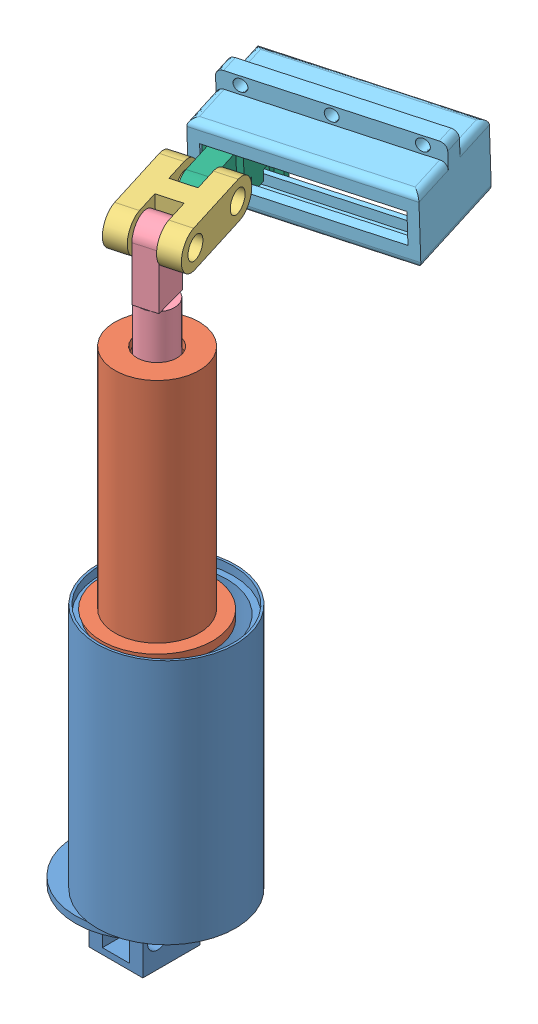
SolidWorks assembly transmission_tele_block_L, configuration Default. Lengths in mm.
Overall size (40.5 112.82 50.09).
7 component instances, 6 part files, 11 mates.
Components (placement in the parent):
- 3rd_tele_part-1: 3rd_tele_part [Default] at (-18.7629 74.2349 7.8731) size (23.75 45.5 20.5)
- 2nd_tele_part-1: 2nd_tele_part [Default] at (-16.8919 75.4849 7.8731) x (0.328664 0 0.944447) z (-0.944447 0 0.328664) size (16.5 35 16.5)
- slider_to_tele-1: slider_to_tele [Default] at (-18.5582 71.8417 -4.2402) x (-0.963773 0 0.266724) z (0.012885 0.998832 0.046558) size (9.53 15 5.5)
- telescopic link-1: telescopic link [Default] at (-15.3258 74.0088 7.4396) x (0.266724 0 0.963773) z (-0.963773 0 0.266724) size (9.2 21.75 9.2)
- transmission_assem-1: transmission_assem [Default] at (-102.7292 -14.6686 -0.1247) x (-0.391198 -0.119011 -0.912579) z (0.837007 0.36623 -0.406564) size (23.67 23.7 33.62)
  - transmissionblockdraft1-1: transmissionblockdraft1 [Default] at (-40.5711 36.7905 123.7047) x (0.976963 0.104487 0.18608) z (-0.13362 -0.380383 0.915125) size (15 12.5 28)
  - transmission_slider-2: transmission_slider [Default] at (-32.9725 47.1445 105.6239) x (0.976963 0.104487 0.18608) z (-0.13362 -0.380383 0.915125) size (21.5 12 5)
Mates (geometry in assembly coordinates):
- Concentric1: concentric: circle of 3rd_tele_part-1; circle of 2nd_tele_part-1
- LimitDistance1: limit distance = 0 mm: plane of 2nd_tele_part-1 through (-18.9461 25.9849 1.9703) normal (0 1 0); plane of 3rd_tele_part-1 through (-25.4371 25.9849 7.8731) normal (0 1 0)
- Concentric2: concentric: circle of 2nd_tele_part-1; circle of 3rd_tele_part-1
- LimitDistance2: limit distance = 2.4761 mm anti-aligned: plane of 2nd_tele_part-1 through (-17.8779 58.4849 5.0397) normal (0 -1 0); plane of telescopic link-1 through (-16.8919 56.0088 7.8731) normal (0 1 0)
- Concentric3: concentric aligned: circle of slider_to_tele-1; circle of telescopic link-1
- Concentric4: concentric anti-aligned: circle of 2nd_tele_part-1; circle of telescopic link-1
- Parallel2: parallel aligned: plane of slider_to_tele-1; plane of transmission_assem-1/transmissionblockdraft1-1
- Concentric5: concentric: circle of slider_to_tele-1; circle of transmission_assem-1/transmission_slider-2
- Coincident11: coincident anti-aligned: circle of slider_to_tele-1; circle of telescopic link-1
- Coincident12: coincident: circle of slider_to_tele-1; circle of transmission_assem-1/transmission_slider-2
- Parallel7: parallel aligned: plane of slider_to_tele-1; plane of transmission_assem-1/transmissionblockdraft1-1
